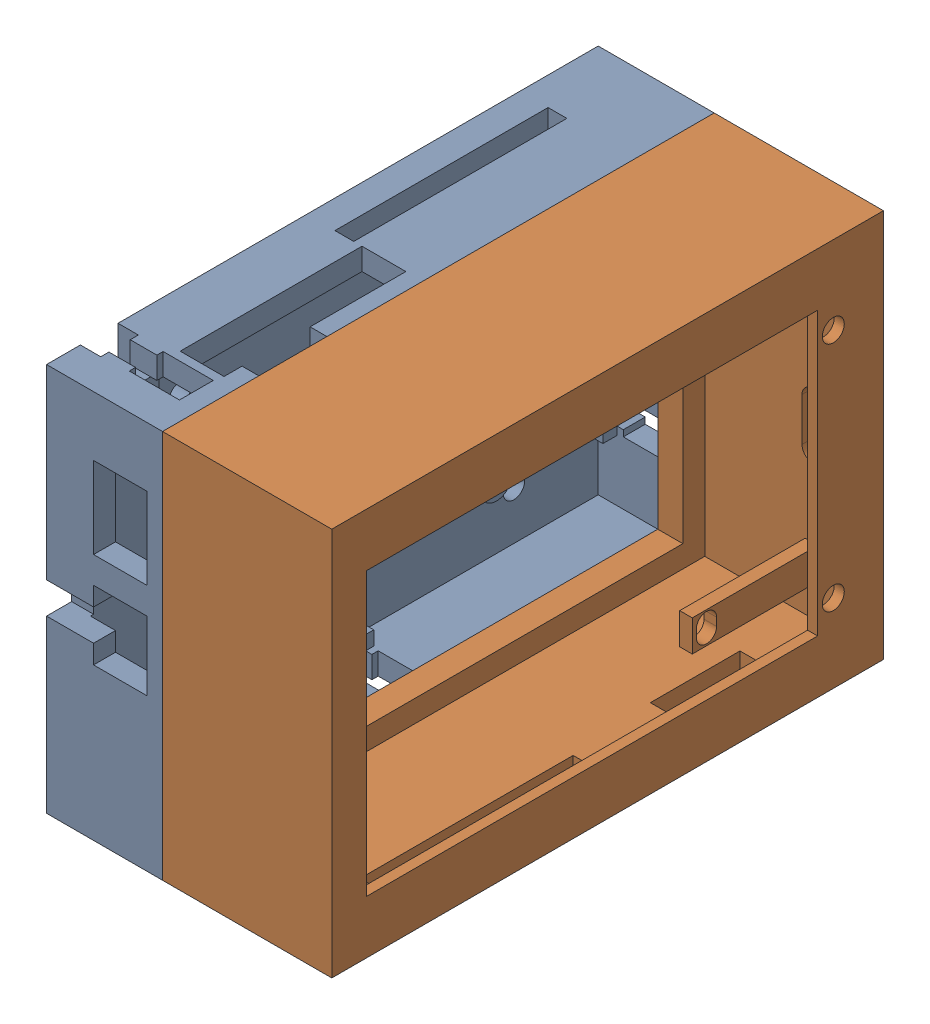
SolidWorks assembly 装配体2, configuration 默认. Lengths in mm.
Overall size (45.5 62 88).
2 component instances, 2 part files, 2 mates.
Components (placement in the parent):
- 主板外壳-1: 主板外壳 [默认] at (-5.8032 -26.4115 40.5) size (18.5 62 88)
- 零件13-1: 零件13 [默认] at (14.6968 32.0885 -44) x (0 0 1) z (-1 0 0) size (88 62 29)
Mates (geometry in assembly coordinates):
- 重合1: coincident: line of 主板外壳-1 through (12.6968 -26.4115 -40.5) axis (0 1 0); line of 零件13-1 through (12.6968 28.5885 -40.5) axis (0 -1 0)
- 重合2: coincident anti-aligned: line of 主板外壳-1 through (12.6968 28.5885 -40.5) axis (0 0 1); line of 零件13-1 through (12.6968 28.5885 40.5) axis (0 0 -1)
